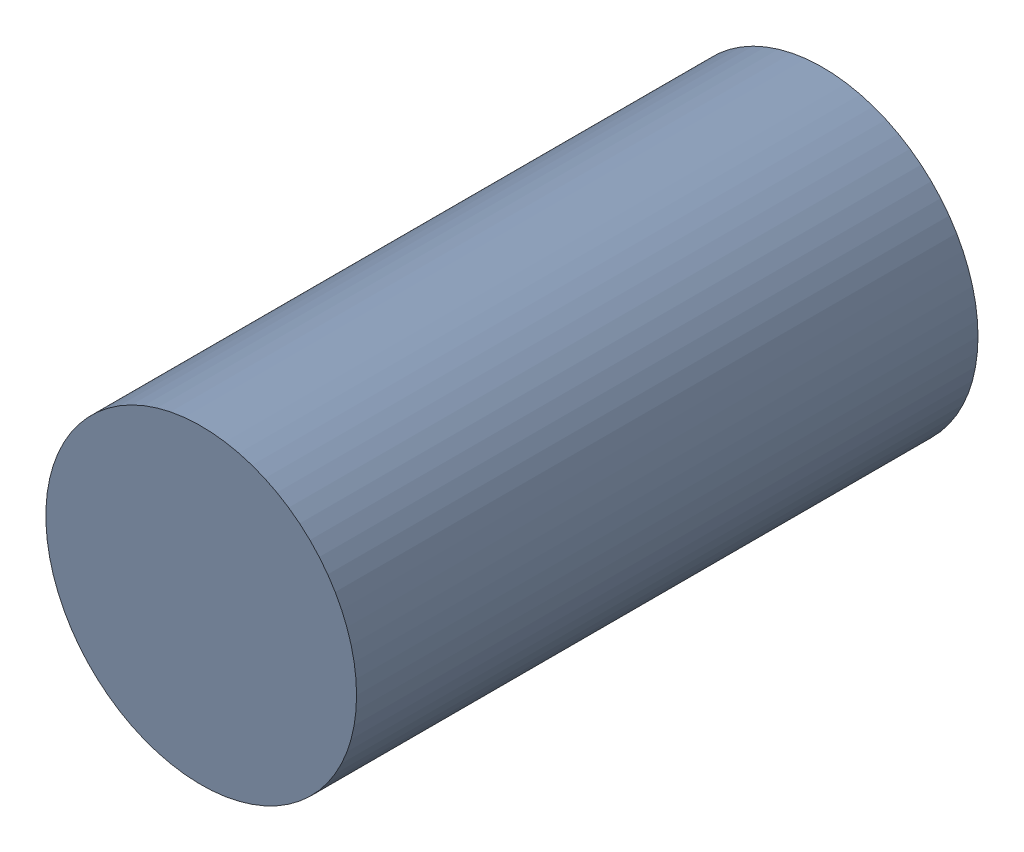
SolidWorks assembly MH7_1.step, configuration Default. Lengths in mm.
Overall size (1 1 2).
2 component instances, 1 part files, 0 mates.
Components (placement in the parent):
- 9228463120_1.step-11: 9228463120_1.step [Default] at (369.9996 241.0004 -1.5) size (1 1 2)
  - Cylinder_1.step-98: Cylinder_1.step [Default] at origin size (1 1 2)
